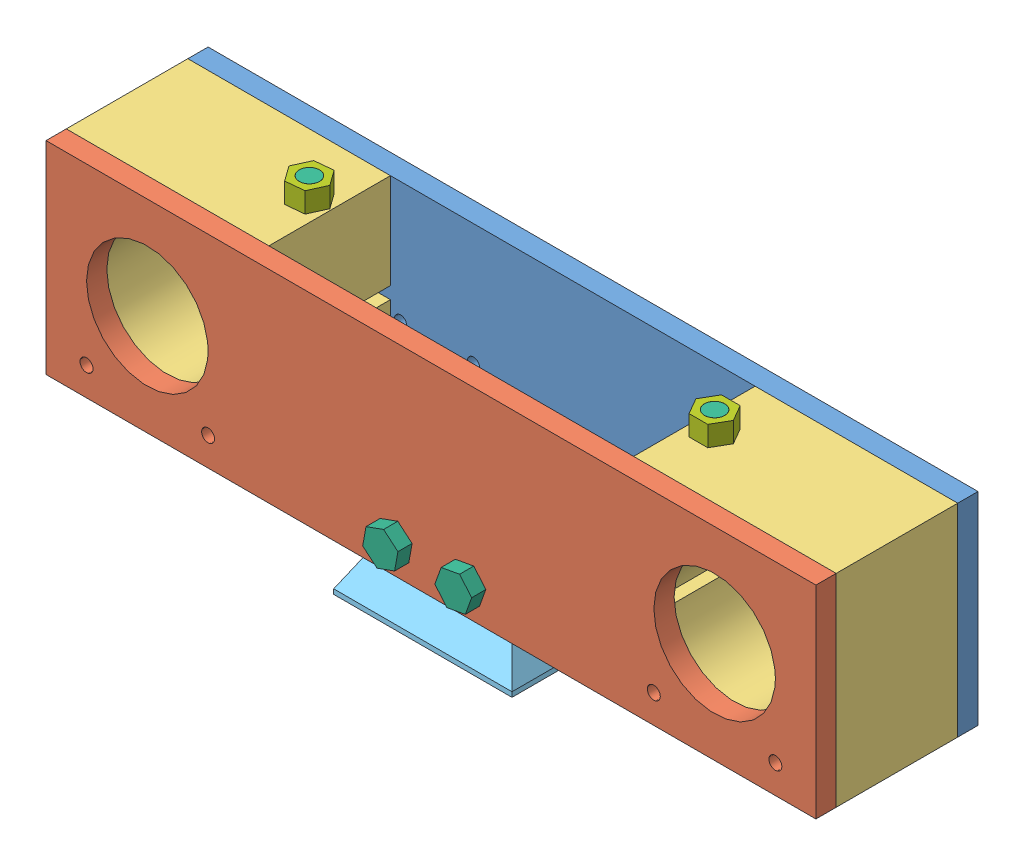
SolidWorks assembly Sideblock_module, configuration Default. Lengths in mm.
Overall size (190 64.5 53.5).
14 component instances, 7 part files, 33 mates.
Components (placement in the parent):
- Sideblock_sideplate_w_beltfastener-6: Sideblock_sideplate_w_beltfastener [Default] at (-0.5228 120.4244 240.321) size (190 50 5)
- Sideblock_sideplate_wo_beltfastener-5: Sideblock_sideplate_wo_beltfastener [Default] at (-0.5228 120.4244 275.321) size (190 50 5)
- Sideblock_tubeFastener-1: Sideblock_tubeFastener [Default] at (49.4772 120.4244 245.321) x (0 1 0) z (0 0 1) size (50 50 30)
- Sideblock_tubeFastener-2: Sideblock_tubeFastener [Default] at (139.4772 120.4244 275.321) x (0 1 0) z (0 0 -1) size (50 50 30)
- Sideblock_belt_fastener-1: Sideblock_belt_fastener [Default] at (73.9772 144.4244 233.321) x (-1 0 0) z (0 0 1) size (26 24 7)
- Tripod_plate_2-1: Tripod_plate_2 [Default] at (72.4772 110.9244 282.321) size (44 24.5 44)
- Tripod_plate_bolt-1: Tripod_plate_bolt [Default] at (85.4772 127.9244 283.821) x (0.940715 0.339197 0) z (-0.339197 0.940715 0) size (9.24 53.5 8)
- Tripod_plate_bolt-2: Tripod_plate_bolt [Default] at (103.4772 127.9244 283.821) x (0.984041 0.177943 0) z (-0.177943 0.984041 0) size (9.24 53.5 8)
- Tripod_plate_nut-1: Tripod_plate_nut [Default] at (103.4772 127.9244 240.321) x (1 0 0) z (0 1 0) size (9.24 5 8)
- Tripod_plate_nut-2: Tripod_plate_nut [Default] at (85.4772 127.9244 240.321) x (1 0 0) z (0 1 0) size (9.24 5 8)
- Tripod_plate_bolt-3: Tripod_plate_bolt [Default] at (44.4772 121.9244 260.321) x (0.866025 0 -0.5) z (0.5 0 0.866025) size (9.24 53.5 8)
- Tripod_plate_bolt-4: Tripod_plate_bolt [Default] at (144.4772 121.9244 260.321) x (0 0 1) z (-1 0 0) size (9.24 53.5 8)
- Tripod_plate_nut-3: Tripod_plate_nut [Default] at (44.4772 170.4244 260.321) x (0.995159 0 -0.098281) z (0.098281 0 0.995159) size (9.24 5 8)
- Tripod_plate_nut-4: Tripod_plate_nut [Default] at (144.4772 170.4244 260.321) size (9.24 5 8)
Mates (geometry in assembly coordinates):
- Concentric1: concentric anti-aligned: circle of Sideblock_sideplate_w_beltfastener-6; cylinder of Sideblock_sideplate_wo_beltfastener-5 through (24.4772 145.4244 280.321) axis (0 0 -1) radius 15
- Concentric2: concentric aligned: cylinder of Sideblock_sideplate_w_beltfastener-6 through (164.4772 145.4244 245.321) axis (0 0 -1) radius 15; cylinder of Sideblock_sideplate_wo_beltfastener-5 through (164.4772 145.4244 280.321) axis (0 0 -1) radius 15
- Distance1: distance = 30 mm anti-aligned: plane of Sideblock_sideplate_w_beltfastener-6 through (-0.5228 120.4244 245.321) normal (0 0 1); plane of Sideblock_sideplate_wo_beltfastener-5 through (-0.5228 120.4244 275.321) normal (0 0 -1)
- Coincident6: coincident anti-aligned: plane of Sideblock_sideplate_w_beltfastener-6 through (-0.5228 120.4244 245.321) normal (0 0 1); plane of Sideblock_tubeFastener-1 through (49.4772 120.4244 245.321) normal (0 0 -1)
- Concentric4: concentric aligned: cylinder of Sideblock_sideplate_wo_beltfastener-5 through (24.4772 145.4244 280.321) axis (0 0 -1) radius 15; cylinder of Sideblock_tubeFastener-1 through (24.4772 145.4244 275.321) axis (0 0 -1) radius 15.2
- Concentric7: concentric anti-aligned: cylinder of Sideblock_sideplate_wo_beltfastener-5 through (164.4772 145.4244 280.321) axis (0 0 -1) radius 15; cylinder of Sideblock_tubeFastener-2 through (164.4772 145.4244 245.321) axis (0 0 1) radius 15.2
- Coincident23: coincident anti-aligned: plane of Sideblock_sideplate_wo_beltfastener-5 through (-0.5228 120.4244 275.321) normal (0 0 -1); plane of Sideblock_tubeFastener-2 through (139.4772 120.4244 275.321) normal (0 0 1)
- Coincident25: coincident anti-aligned: plane of Sideblock_sideplate_w_beltfastener-6 through (-0.5228 120.4244 240.321) normal (0 0 -1); plane of Sideblock_belt_fastener-1 through (73.9772 144.4244 240.321) normal (0 0 1)
- Coincident26: coincident aligned: plane of Sideblock_sideplate_wo_beltfastener-5 through (-0.5228 170.4244 280.321) normal (0 1 0); plane of Sideblock_tubeFastener-1 through (49.4772 170.4244 275.321) normal (0 1 0)
- Coincident27: coincident aligned: plane of Sideblock_sideplate_wo_beltfastener-5 through (-0.5228 170.4244 280.321) normal (0 1 0); plane of Sideblock_tubeFastener-2 through (139.4772 170.4244 245.321) normal (0 1 0)
- Concentric13: concentric anti-aligned: cylinder of Sideblock_sideplate_w_beltfastener-6 through (85.4772 127.9244 245.321) axis (0 0 -1) radius 3; cylinder of Tripod_plate_bolt-1 through (85.4772 127.9244 230.321) axis (0 0 1) radius 2.5
- Concentric14: concentric anti-aligned: cylinder of Sideblock_sideplate_w_beltfastener-6 through (103.4772 127.9244 245.321) axis (0 0 -1) radius 3; cylinder of Tripod_plate_bolt-2 through (103.4772 127.9244 230.321) axis (0 0 1) radius 2.5
- Coincident35: coincident anti-aligned: plane of Sideblock_sideplate_wo_beltfastener-5 through (-0.5228 120.4244 280.321) normal (0 0 1); plane of Tripod_plate_bolt-1 through (85.4772 127.9244 280.321) normal (0 0 -1)
- Coincident36: coincident anti-aligned: plane of Sideblock_sideplate_wo_beltfastener-5 through (-0.5228 120.4244 280.321) normal (0 0 1); plane of Tripod_plate_bolt-2 through (103.4772 127.9244 280.321) normal (0 0 -1)
- Concentric17: concentric anti-aligned: cylinder of Tripod_plate_bolt-2 through (103.4772 127.9244 230.321) axis (0 0 1) radius 2.5; cylinder of Tripod_plate_nut-1 through (103.4772 127.9244 240.321) axis (0 0 -1) radius 2.5
- Concentric18: concentric anti-aligned: cylinder of Tripod_plate_bolt-1 through (85.4772 127.9244 230.321) axis (0 0 1) radius 2.5; cylinder of Tripod_plate_nut-2 through (85.4772 127.9244 240.321) axis (0 0 -1) radius 2.5
- Coincident37: coincident anti-aligned: plane of Sideblock_sideplate_w_beltfastener-6 through (-0.5228 120.4244 240.321) normal (0 0 -1); plane of Tripod_plate_nut-2 through (85.4772 127.9244 240.321) normal (0 0 1)
- Coincident38: coincident anti-aligned: plane of Sideblock_sideplate_w_beltfastener-6 through (-0.5228 120.4244 240.321) normal (0 0 -1); plane of Tripod_plate_nut-1 through (103.4772 127.9244 240.321) normal (0 0 1)
- Width2: width anti-aligned: plane of Sideblock_tubeFastener-1 through (41.8272 116.4244 258.791) normal (1 0 0); plane of Sideblock_tubeFastener-1 through (47.1272 116.4244 261.851) normal (-1 0 0); cylinder of Tripod_plate_bolt-3 through (44.4772 175.4244 260.321) axis (0 -1 0) radius 2.5
- Width3: width anti-aligned: plane of Sideblock_tubeFastener-1 through (47.1272 116.4244 258.791) normal (-0.5 0 0.866025); plane of Sideblock_tubeFastener-1 through (41.8272 116.4244 261.851) normal (0.5 0 -0.866025); cylinder of Tripod_plate_bolt-3 through (44.4772 175.4244 260.321) axis (0 -1 0) radius 2.5
- Coincident41: coincident anti-aligned: plane of Sideblock_tubeFastener-1 through (49.4772 125.4244 245.321) normal (0 -1 0); plane of Tripod_plate_bolt-3 through (44.4772 125.4244 260.321) normal (0 1 0)
- Width4: width anti-aligned: plane of Sideblock_tubeFastener-2 through (141.8272 116.4244 258.791) normal (1 0 0); plane of Sideblock_tubeFastener-2 through (147.1272 116.4244 261.851) normal (-1 0 0); cylinder of Tripod_plate_bolt-4 through (144.4772 175.4244 260.321) axis (0 -1 0) radius 2.5
- Width5: width anti-aligned: plane of Sideblock_tubeFastener-2 through (144.4772 116.4244 263.381) normal (-0.5 0 -0.866025); plane of Sideblock_tubeFastener-2 through (144.4772 116.4244 257.261) normal (0.5 0 0.866025); cylinder of Tripod_plate_bolt-4 through (144.4772 175.4244 260.321) axis (0 -1 0) radius 2.5
- Concentric19: concentric anti-aligned: cylinder of Tripod_plate_bolt-4 through (144.4772 175.4244 260.321) axis (0 -1 0) radius 2.5; cylinder of Tripod_plate_nut-4 through (144.4772 170.4244 260.321) axis (0 1 0) radius 2.5
- Concentric20: concentric anti-aligned: cylinder of Tripod_plate_bolt-3 through (44.4772 175.4244 260.321) axis (0 -1 0) radius 2.5; cylinder of Tripod_plate_nut-3 through (44.4772 170.4244 260.321) axis (0 1 0) radius 2.5
- Coincident44: coincident anti-aligned: plane of Sideblock_tubeFastener-1 through (49.4772 170.4244 275.321) normal (0 1 0); plane of Tripod_plate_nut-3 through (44.4772 170.4244 260.321) normal (0 -1 0)
- Parallel1: parallel anti-aligned: plane of Sideblock_tubeFastener-1 through (40.3272 125.4244 257.925) normal (0.5 0 0.866025); plane of Tripod_plate_bolt-3 through (44.4772 125.4244 255.7022) normal (-0.5 0 -0.866025)
- Parallel2: parallel anti-aligned: plane of Sideblock_tubeFastener-2 through (148.6272 125.4244 262.717) normal (-0.5 0 -0.866025); plane of Tripod_plate_bolt-4 through (144.4772 125.4244 264.9398) normal (0.5 0 0.866025)
- Coincident49: coincident anti-aligned: plane of Sideblock_tubeFastener-2 through (139.4772 125.4244 275.321) normal (0 -1 0); plane of Tripod_plate_bolt-4 through (144.4772 125.4244 260.321) normal (0 1 0)
- Width6: width anti-aligned: plane of Tripod_plate_2-1 through (82.7272 129.5121 238.321) normal (1 0 0); plane of Tripod_plate_2-1 through (88.2272 126.3367 238.321) normal (-1 0 0); cylinder of Tripod_plate_bolt-1 through (85.4772 127.9244 230.321) axis (0 0 1) radius 2.5
- Width7: width anti-aligned: plane of Tripod_plate_2-1 through (88.2272 129.5121 238.321) normal (-0.5 -0.866025 0); plane of Tripod_plate_2-1 through (82.7272 126.3367 238.321) normal (0.5 0.866025 0); cylinder of Tripod_plate_bolt-1 through (85.4772 127.9244 230.321) axis (0 0 1) radius 2.5
- Parallel3: parallel aligned: plane of Sideblock_sideplate_w_beltfastener-6 through (-0.5228 170.4244 245.321) normal (0 1 0); plane of Tripod_plate_2-1 through (72.4772 135.4244 282.321) normal (0 1 0)
- Coincident50: coincident anti-aligned: plane of Sideblock_sideplate_w_beltfastener-6 through (-0.5228 120.4244 245.321) normal (0 0 1); plane of Tripod_plate_2-1 through (77.4772 135.4244 245.321) normal (0 0 -1)
